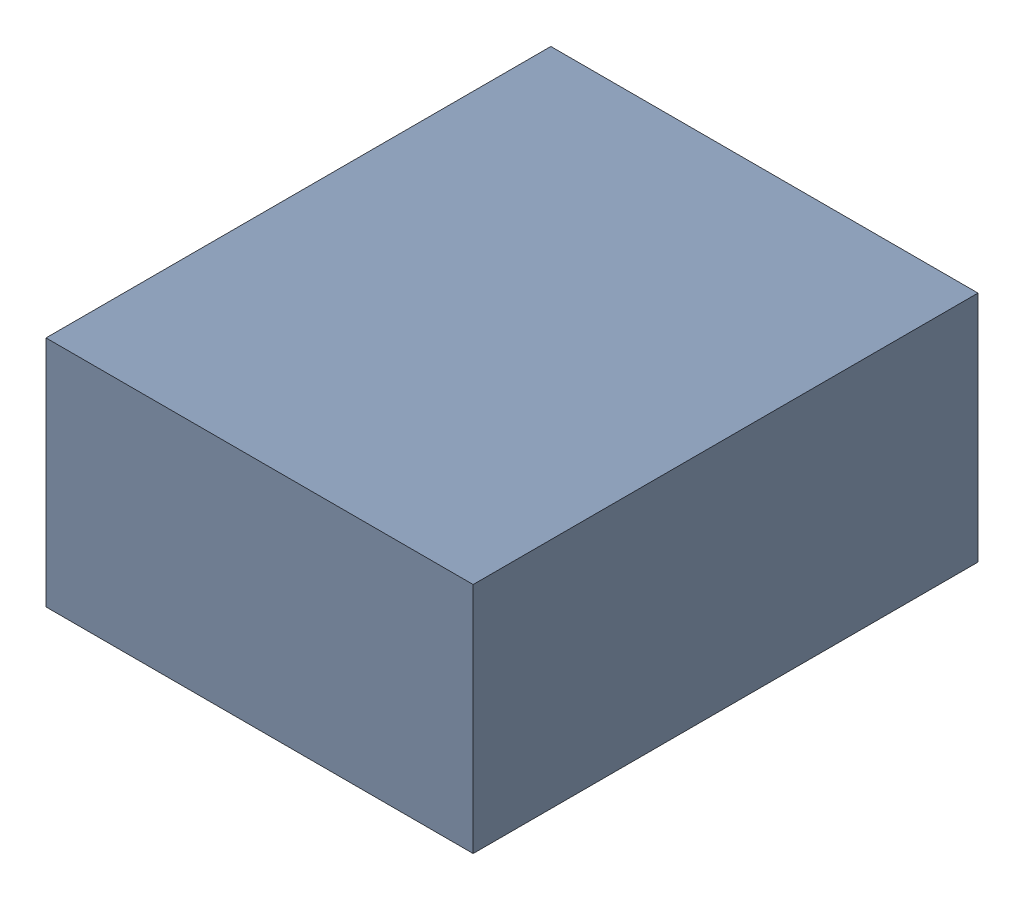
SolidWorks assembly C6, configuration Standard. Lengths in mm.
Overall size (1.1 0.6 1.3).
2 component instances, 1 part files, 0 mates.
Components (placement in the parent):
- 885542240-1: 885542240 [Standard] at (-2.9 -12.85 0) size (1.1 0.6 1.3)
  - Extruded_28-1: Extruded_28 [Standard] at origin size (1.1 0.6 1.3)
